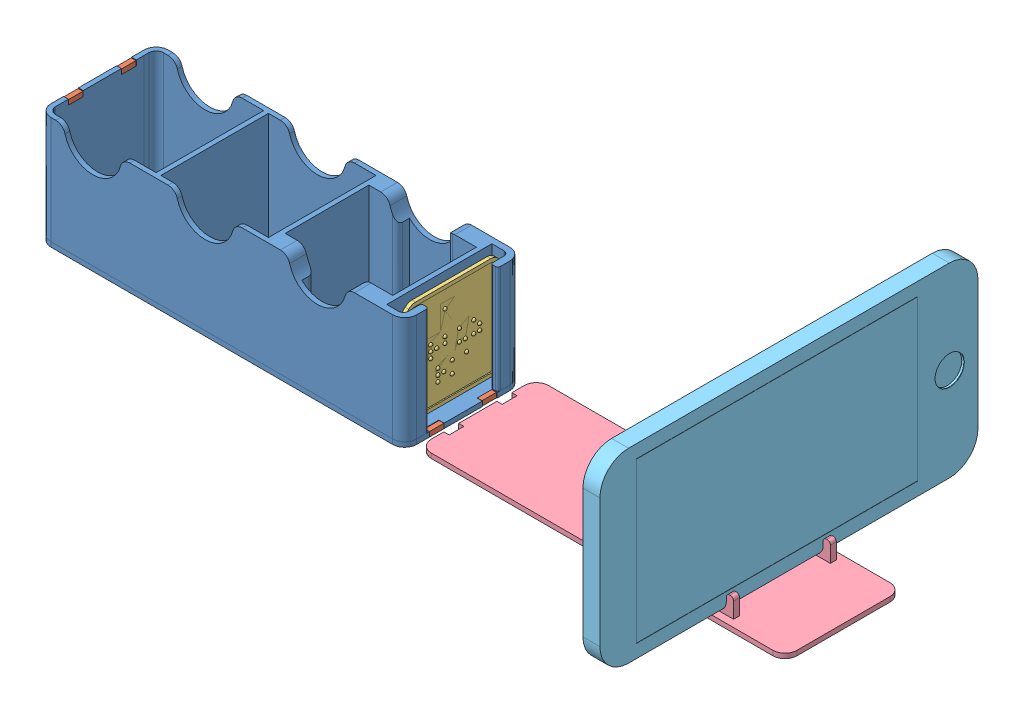
SolidWorks assembly full-assembly, configuration По умолчанию. Lengths in mm.
Overall size (311.64 84.04 158.2).
9 component instances, 5 part files, 6 mates.
Components (placement in the parent):
- box-assembly-1: box-assembly [По умолчанию] at origin size (153 47 49)
  - box-1: box [По умолчанию] at origin size (153 47 49)
  - magnet-prism-6x2x2-1: magnet-prism-6x2x2 [По умолчанию] at (-75.5 42.8 11.1) x (0 0 1) z (-1 0 0) size (6 2 2)
  - magnet-prism-6x2x2-2: magnet-prism-6x2x2 [По умолчанию] at (-75.5 42.8 -11.1) x (0 0 1) z (-1 0 0) size (6 2 2)
  - magnet-prism-6x2x2-10: magnet-prism-6x2x2 [По умолчанию] at (75.5 -2 11.1) x (0 0 -1) z (1 0 0) size (6 2 2)
  - magnet-prism-6x2x2-12: magnet-prism-6x2x2 [По умолчанию] at (75.3 0 -11.1) x (0 0 -1) z (-1 0 0) size (6 2 2)
  - а-арбуз-арка-1: а-арбуз-арка [По умолчанию] at (69 22.3399 0) x (0 0 -1) z (0 -1 0) size (43 1.75 43)
- lid-1: lid [По умолчанию] at (158.6436 2.5096 -0.4604) size (153 32 49)
- iphone6splus-1: iphone6splus [По умолчанию] at (199.1225 43.0937 -6.5588) x (0 1 0) z (0 0 -1) size (77.9 7.1 158.2)
Mates (geometry in assembly coordinates):
- Параллельность1: parallel anti-aligned: plane of lid-1 through (158.6436 2.5096 -0.4604) normal (0 1 0); plane of iphone6splus-1 through (206.2225 4.1437 60.5412) normal (0 -1 0)
- Параллельность2: parallel anti-aligned: plane of lid-1 through (158.6436 2.5096 -0.4604) normal (0 1 0); plane of iphone6splus-1 through (206.2225 4.1437 60.5412) normal (0 -1 0)
- Параллельность3: parallel aligned: plane of lid-1 through (190.6436 2.5096 18.5396) normal (-1 0 0); plane of iphone6splus-1 through (199.1225 70.0437 -73.6588) normal (-1 0 0)
- Параллельность4: parallel: plane of box-assembly-1/box-1 through (0 0 0) normal (0 1 0); plane of ? through (0 0.8576 0) normal (0 -1 0)
- Совпадение3: coincident: plane of box-assembly-1/box-1 through (-76.5 45 0) normal (-1 0 0); plane of ? through (-76.5 2.8576 0) normal (-1 0 0)
- Совпадение4: coincident aligned: plane of box-assembly-1/box-1 through (0 45 -24.5) normal (0 0 -1); plane of ? through (0 2.8576 -24.5) normal (0 0 -1)
